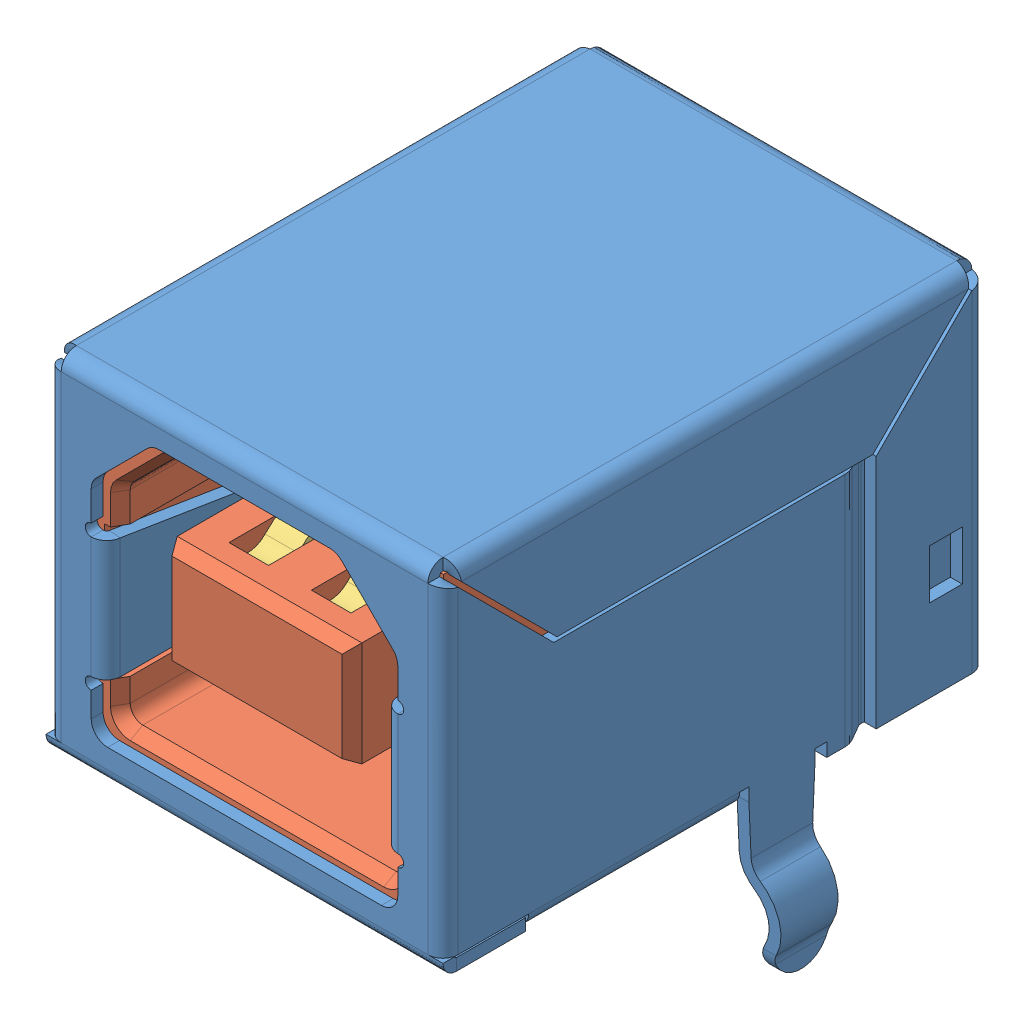
SolidWorks assembly USB type b.SL100001-10001-3-0PRT.SL100001-10001-3-0ASM, configuration Default. Lengths in mm.
Overall size (14.34 15.2 16.54).
6 component instances, 4 part files, 9 mates.
Components (placement in the parent):
- USB SHELL.SL100001-10001-3-0PRT-1: USB SHELL.SL100001-10001-3-0PRT [Default] at origin size (14.34 15.2 16.54)
- USB core.SL100001-10001-3-0PRT-1: USB core.SL100001-10001-3-0PRT [Default] at origin size (11.3 10.68 15.75)
- usb top contact.SL100001-10001-3-0PRT-1: usb top contact.SL100001-10001-3-0PRT [Default] at (1.25 6.09 -0.38) size (1 9.67 13.76)
- usb btm contact.SL100001-10001-3-0PRT-1: usb btm contact.SL100001-10001-3-0PRT [Default] at (1.25 4.41 -0.38) size (1 6.84 11.76)
- usb btm contact.SL100001-10001-3-0PRT-2: usb btm contact.SL100001-10001-3-0PRT [Default] at (-1.25 4.41 -0.38) size (1 6.84 11.76)
- usb top contact.SL100001-10001-3-0PRT-2: usb top contact.SL100001-10001-3-0PRT [Default] at (-1.25 6.09 -0.38) size (1 9.67 13.76)
Mates (geometry in assembly coordinates):
- Coincident1: coincident aligned: plane of USB SHELL.SL100001-10001-3-0PRT-1 through (0 0 0) normal (1 0 0); plane of USB core.SL100001-10001-3-0PRT-1 through (0 0 0) normal (1 0 0)
- Coincident2: coincident aligned: plane of USB SHELL.SL100001-10001-3-0PRT-1 through (0 0 0) normal (0 0 1); plane of USB core.SL100001-10001-3-0PRT-1 through (0 0 0) normal (0 0 1)
- Coincident3: coincident aligned: plane of USB SHELL.SL100001-10001-3-0PRT-1 through (0 0 0) normal (0 1 0); plane of USB core.SL100001-10001-3-0PRT-1 through (0 0 0) normal (0 1 0)
- Distance1: distance = 1.25 mm aligned: plane of usb top contact.SL100001-10001-3-0PRT-1 through (1.25 6.09 -0.38) normal (1 0 0); plane of USB SHELL.SL100001-10001-3-0PRT-1 through (0 0 0) normal (1 0 0)
- Coincident5: coincident aligned: plane of USB core.SL100001-10001-3-0PRT-1 through (0.65 6.09 -16.1301) normal (0 1 0); plane of usb top contact.SL100001-10001-3-0PRT-1 through (1.25 6.09 -0.38) normal (0 1 0)
- Coincident6: coincident aligned: plane of USB core.SL100001-10001-3-0PRT-1 through (0 0 -0.38) normal (0 0 1); plane of usb top contact.SL100001-10001-3-0PRT-1 through (1.25 6.09 -0.38) normal (0 0 1)
- Distance2: distance = 1.25 mm aligned: plane of usb btm contact.SL100001-10001-3-0PRT-1 through (1.25 4.41 -0.38) normal (1 0 0); plane of USB SHELL.SL100001-10001-3-0PRT-1 through (0 0 0) normal (1 0 0)
- Coincident8: coincident anti-aligned: plane of USB core.SL100001-10001-3-0PRT-1 through (0.65 4.41 -16.1301) normal (0 -1 0); plane of usb btm contact.SL100001-10001-3-0PRT-1 through (1.25 4.41 -0.38) normal (0 1 0)
- Coincident9: coincident aligned: plane of USB core.SL100001-10001-3-0PRT-1 through (0 0 -0.38) normal (0 0 1); plane of usb btm contact.SL100001-10001-3-0PRT-1 through (1.25 4.41 -0.38) normal (0 0 1)
